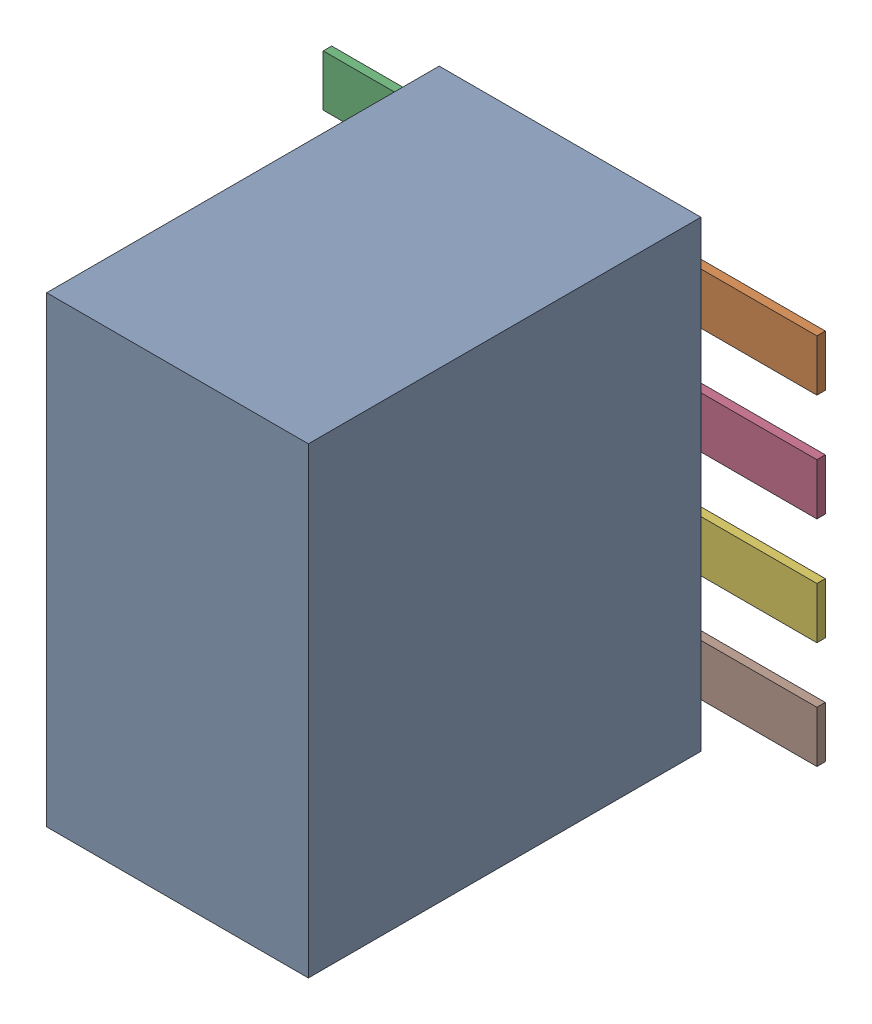
SolidWorks assembly J12_1.step, configuration Default. Lengths in mm.
Overall size (5.85 5.48 4.75).
3 component instances, 2 part files, 0 mates.
Components (placement in the parent):
- 9452611696_1.step-11: 9452611696_1.step [Default] at (493.2934 266.0396 0) x (0 -1 0) z (0 0 1) size (5.48 5.85 4.75)
  - Body_2.step-11: Body_2.step [Default] at (0 0 0.1) size (5.48 3.1 4.65)
  - Pins_1.step-11: Pins_1.step [Default] at origin size (4.42 5.85 0.1)
